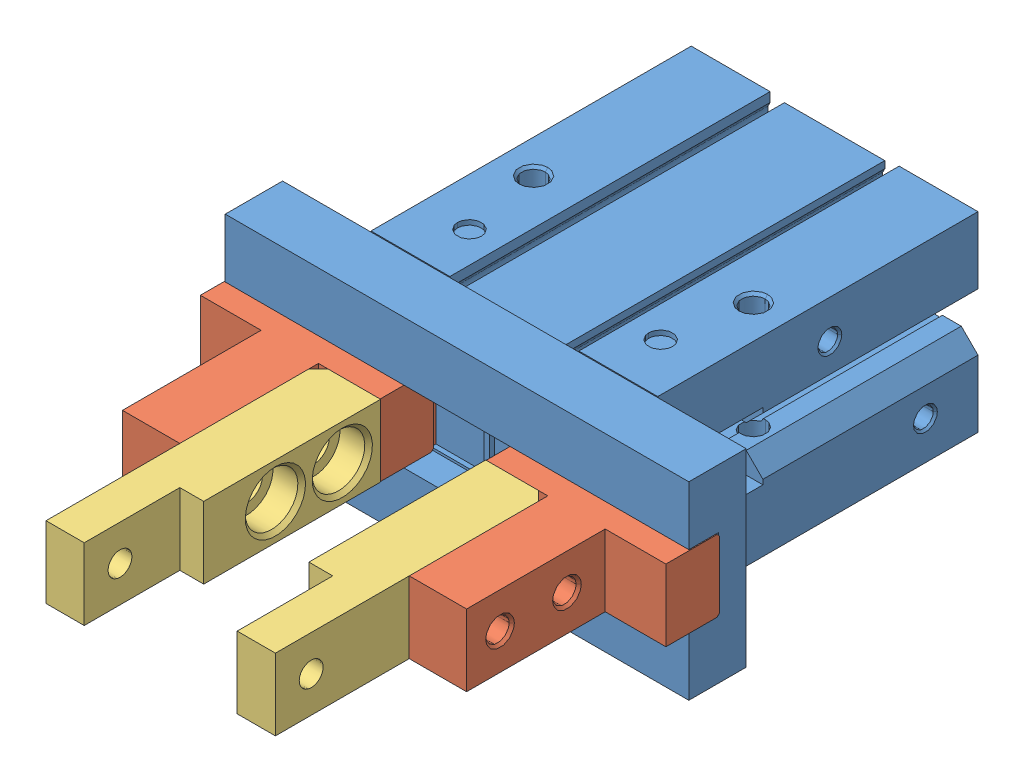
SolidWorks assembly Montagem Com Movimento Completa, configuration Default. Lengths in mm.
Overall size (97.4 40 141).
5 component instances, 3 part files, 10 mates.
Components (placement in the parent):
- _MHZ2-32D_Body(0)-1: _MHZ2-32D_Body(0) [Défaut] at origin size (97 40 79)
- Montagem Grippers-1: Montagem Grippers [Défaut] at (0 0 72.8) size (37.6 15 41.2)
- Montagem Grippers-2: Montagem Grippers [Défaut] at (0 0 72.8) x (-1 0 0) z (0 0 1) size (37.6 15 41.2)
- pinça2-1: pinça2 [Valor predeterminado] at (-41.015 -36.4419 86.6295) x (1 0 0) z (0 -1 0) size (13 57 15)
- pinça2-2: pinça2 [Valor predeterminado] at (41.015 36.4419 86.6295) x (-1 0 0) z (0 1 0) size (13 57 15)
Mates (geometry in assembly coordinates):
- Coincidente1: coincident: plane of assembly; plane of assembly; plane of _MHZ2-32D_Body(0)-1 through (48.5 7.5 72.8) normal (0 0 1); plane of Montagem Grippers-2 through (11.1 -7.5 72.8) normal (0 0 -1)
- Coincidente2: coincident: plane of assembly; plane of assembly; plane of _MHZ2-32D_Body(0)-1 through (48.5 7.5 79) normal (0 -1 0); plane of Montagem Grippers-2 through (0 7.5 72.8) normal (0 1 0)
- DistânciaLimite1: limit distance = 11 mm: plane of assembly; plane of assembly; plane of Montagem Grippers-2 through (11.6 0 72.8) normal (-1 0 0); plane of _MHZ2-32D_Body(0)-1 through (0.6 7 71.8) normal (1 0 0)
- Coincidente3: coincident: plane of assembly; plane of assembly; plane of _MHZ2-32D_Body(0)-1 through (48.5 -7.5 72.8) normal (0 1 0); plane of Montagem Grippers-1 through (0 -7.5 72.8) normal (0 -1 0)
- Coincidente4: coincident: plane of assembly; plane of assembly; plane of _MHZ2-32D_Body(0)-1 through (48.5 7.5 72.8) normal (0 0 1); plane of Montagem Grippers-1 through (-11.1 7.5 72.8) normal (0 0 -1)
- DistânciaLimite2: limit distance = 11 mm: plane of assembly; plane of assembly; plane of Montagem Grippers-1 through (-11.6 0 72.8) normal (1 0 0); plane of _MHZ2-32D_Body(0)-1 through (-0.6 -7 71.8) normal (-1 0 0)
- Concêntrico1: concentric: cylinder of assembly; cylinder of assembly; cylinder of Montagem Grippers-1 through (-36 0 106) axis (1 0 0) radius 2.4585; cylinder of pinça2-2 through (11 0 106) axis (-1 0 0) radius 3.3
- Concêntrico2: concentric: cylinder of assembly; cylinder of assembly; cylinder of Montagem Grippers-2 through (36 0 106) axis (-1 0 0) radius 2.4585; cylinder of pinça2-1 through (-11 0 106) axis (1 0 0) radius 3.3
- Coincidente6: coincident: plane of assembly; plane of assembly; plane of Montagem Grippers-2 through (24 -7.5 113) normal (-1 0 0); plane of pinça2-2 through (24 55.7965 184.0764) normal (1 0 0)
- Coincidente7: coincident: plane of assembly; plane of assembly; plane of Montagem Grippers-1 through (-24 7.5 113) normal (1 0 0); plane of pinça2-1 through (-24 -55.7965 184.0764) normal (-1 0 0)
